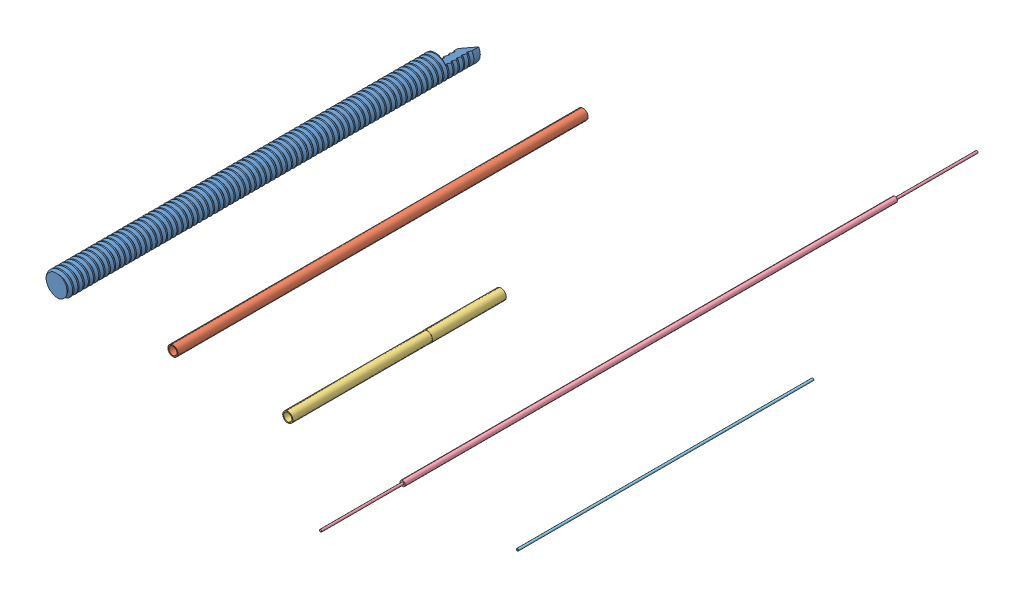
SolidWorks assembly NeededItems, configuration Default. Lengths in mm.
Overall size (28.89 1.64 40).
5 component instances, 5 part files, 4 mates.
Components (placement in the parent):
- drive_threaded_rod_25mm-1: drive_threaded_rod_25mm [Default] x (-1 0 0) z (0 -1 0) size (1.64 25.22 1.64)
- stabilizer_23g_25mm-1: stabilizer_23g_25mm [Default] at (7 0 0) x (-1 0 0) z (0 -1 0) size (0.62 25 0.62)
- guide_23g_13mm-1: guide_23g_13mm [Default] at (14 0 0) x (-1 0 0) z (0 -1 0) size (0.64 13 0.64)
- 30g_straight-1: 30g_straight [Default] at (21 0 -6) x (-1 0 0) z (0 -1 0) size (0.32 40 0.32)
- polyimide_sheath-1: polyimide_sheath [Default] at (28 0 0) x (1 0 0) z (0 1 0) size (0.13 18 0.13)
Mates (geometry in assembly coordinates):
- Coincident2: coincident anti-aligned: circle of guide_23g_13mm-1; plane of assembly through (0 0 0) normal (0 0 1)
- Coincident3: coincident anti-aligned: circle of stabilizer_23g_25mm-1; plane of assembly through (0 0 0) normal (0 0 1)
- Coincident4: coincident anti-aligned: circle of 30g_straight-1; plane of assembly through (0 0 0) normal (0 0 1)
- Coincident5: coincident anti-aligned: circle of drive_threaded_rod_25mm-1; plane of assembly through (0 0 0) normal (0 0 1)
